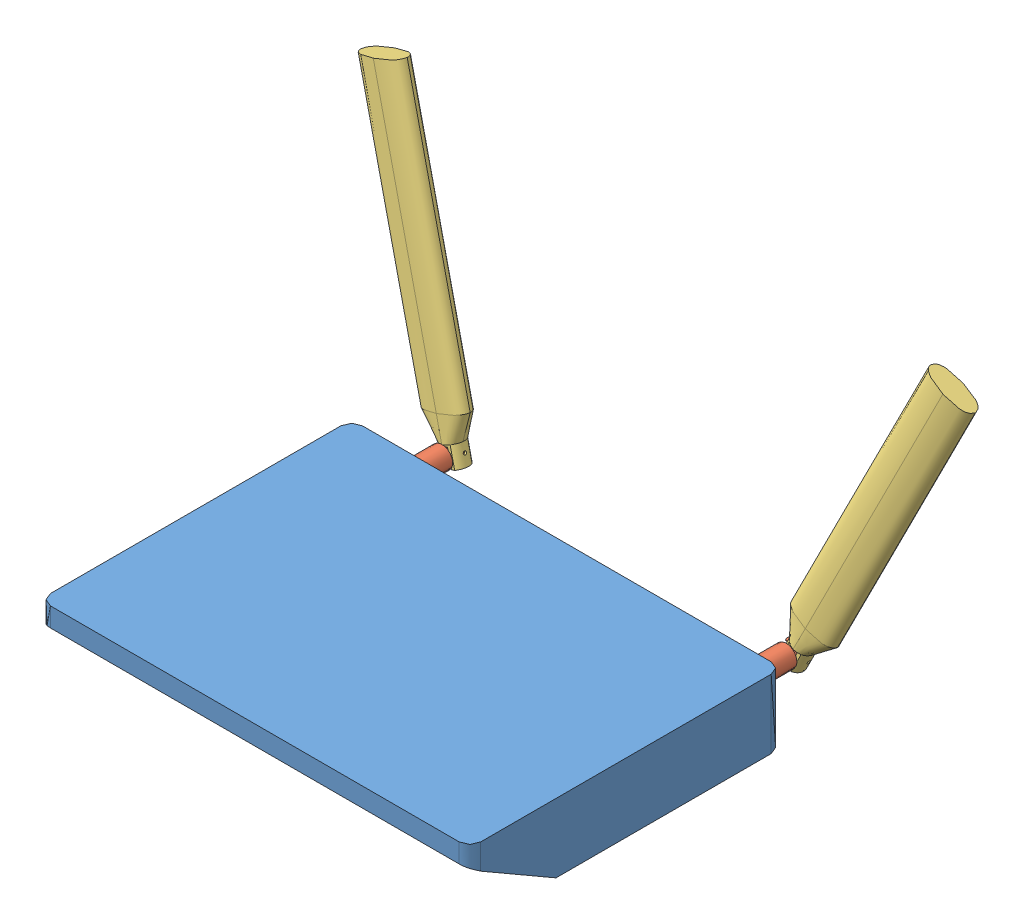
SolidWorks assembly MT7986A_3D, configuration Default. Lengths in mm.
Overall size (282.63 152.6 191.63).
5 component instances, 3 part files, 11 mates.
Components (placement in the parent):
- TPLinkMR400-Body-01-1: TPLinkMR400-Body-01 [Default] at (-100 0 -72.5) size (200 32 155)
- Ant-Ex1-1: Ant-Ex1 [Default] at (-180 16 -147) x (-0.948235 -0.317569 0) z (0 0 -1) size (10 10 27.5)
- Ant-Ex2-1: Ant-Ex2 [Default] at (-223.3437 148.6268 -183.5102) x (0.948235 0.317569 0) z (0.316495 -0.945028 0.08218) size (22.52 10.1 145)
- Ant-Ex1-2: Ant-Ex1 [Default] at (-20 16 -147) x (-0.912169 0.409815 0) z (0 0 -1) size (10 10 27.5)
- Ant-Ex2-2: Ant-Ex2 [Default] at (37.9898 142.5895 -186.6055) x (0.912169 -0.409815 0) z (-0.40758 -0.907195 0.10429) size (22.52 10.1 145)
Mates (geometry in assembly coordinates):
- Coincident62: coincident: circle of TPLinkMR400-Body-01-1; plane of Ant-Ex1-1 through (-180 16 -147) normal (0 0 1)
- Concentric5: concentric: cylinder of TPLinkMR400-Body-01-1 through (-180 16 -155) axis (0 0 1) radius 4; cylinder of Ant-Ex1-1 through (-180 16 -167) axis (0 0 1) radius 5
- Concentric6: concentric: cylinder of Ant-Ex1-1 through (-184.7412 14.4122 -172) axis (0.948235 0.317569 0) radius 0.75; cylinder of Ant-Ex2-1 through (-183.7756 14.7355 -172) axis (0.948235 0.317569 0) radius 0.75
- Coincident63: coincident: plane of Ant-Ex1-1 through (-178.4233 19.1645 -174.5) normal (0.948235 0.317569 0); plane of Ant-Ex2-1 through (-178.5005 19.3948 -175.2416) normal (-0.948235 -0.317569 0)
- Coincident64: coincident: plane of TPLinkMR400-Body-01-1 through (-20 16 -147) normal (0 0 -1); plane of Ant-Ex1-2 through (-20 16 -147) normal (0 0 1)
- Concentric7: concentric: cylinder of TPLinkMR400-Body-01-1 through (-20 16 -155) axis (0 0 1) radius 4; cylinder of Ant-Ex1-2 through (-20 16 -167) axis (0 0 1) radius 5
- Concentric8: concentric: cylinder of Ant-Ex1-2 through (-15.4392 13.9509 -172) axis (-0.912169 0.409815 0) radius 0.75; cylinder of Ant-Ex2-2 through (-23.632 17.6318 -172) axis (0.912169 -0.409815 0) radius 0.75
- Coincident65: coincident: plane of Ant-Ex1-2 through (-16.695 17.2559 -174.5) normal (0.912169 -0.409815 0); plane of Ant-Ex2-2 through (-16.6253 17.4112 -175.3017) normal (-0.912169 0.409815 0)
- Coincident66: coincident: plane of TPLinkMR400-Body-01-1 through (-100 0 -72.5) normal (0 -1 0); plane of assembly through (0 0 0) normal (0 1 0)
- Coincident67: coincident: plane of TPLinkMR400-Body-01-1 through (0 32 0) normal (1 0 0); plane of assembly through (0 0 0) normal (1 0 0)
- Coincident68: coincident: plane of TPLinkMR400-Body-01-1 through (-200 32 0) normal (0 0 1); plane of assembly through (0 0 0) normal (0 0 1)
